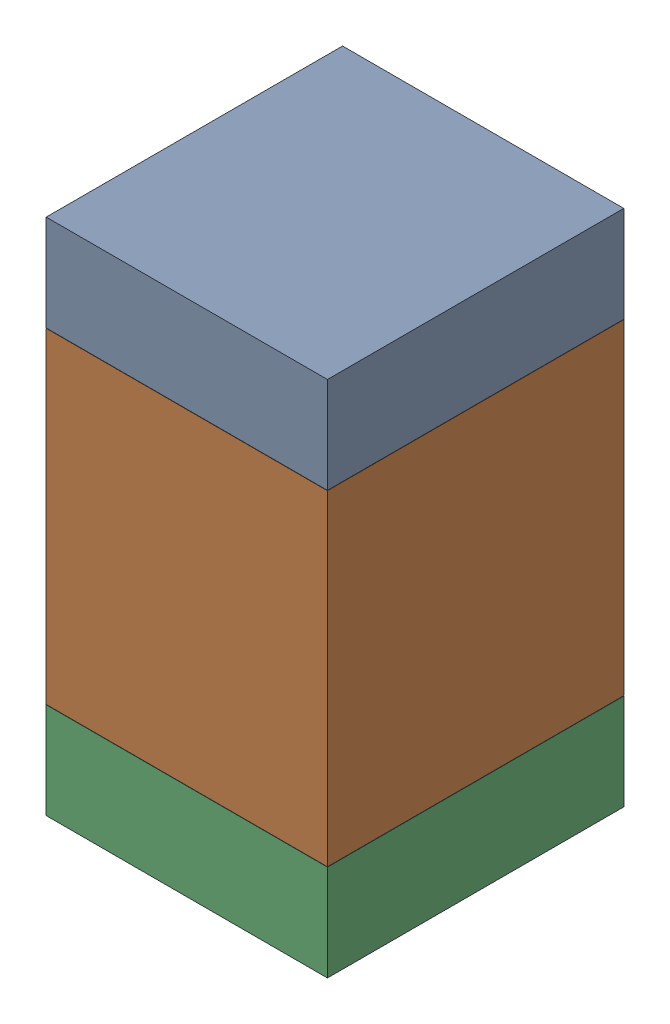
SolidWorks assembly C15, configuration Default. Lengths in mm.
Overall size (0.95 1.75 1).
6 component instances, 2 part files, 0 mates.
Components (placement in the parent):
- 6575495072-1: 6575495072 [Default] at (9.652 15.8255 0) size (0.95 0.32 1)
  - Extruded_6-1: Extruded_6 [Default] at origin size (0.95 0.32 1)
- 6575494912-1: 6575494912 [Default] at (9.652 15.113 0) size (0.95 1.1 1)
  - Extruded_7-1: Extruded_7 [Default] at origin size (0.95 1.1 1)
- 6575495072-2: 6575495072 [Default] at (9.652 14.4005 0) size (0.95 0.32 1)
  - Extruded_6-1: Extruded_6 [Default] at origin size (0.95 0.32 1)
